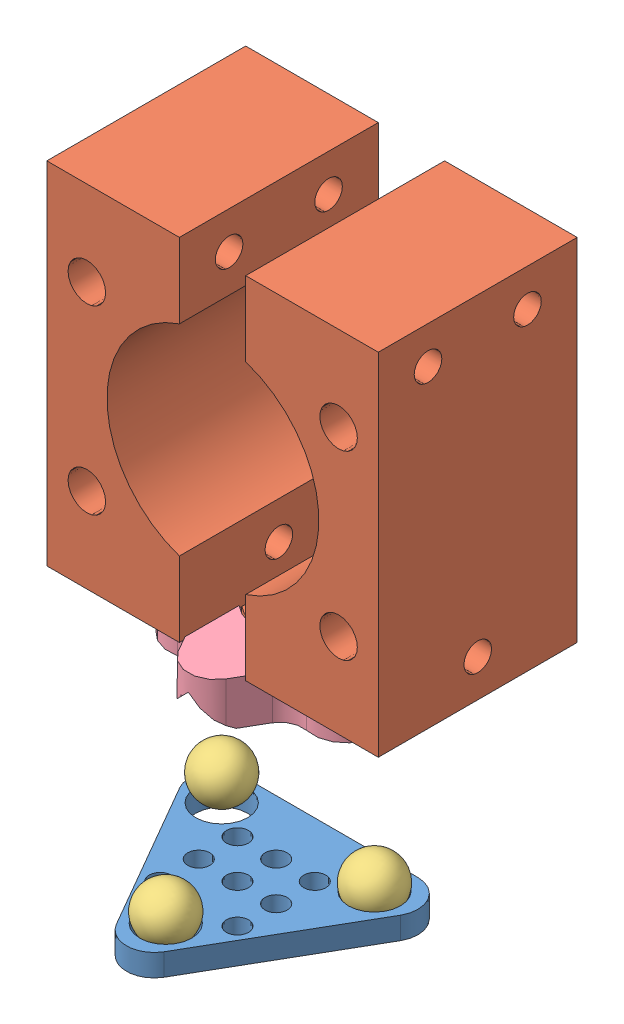
SolidWorks assembly Assembly Ball ground hat magnet, configuration Default. Lengths in mm.
Overall size (30.8 48.2 32.89).
6 component instances, 4 part files, 6 mates.
Components (placement in the parent):
- TricornerHat-1: TricornerHat [Default] at (-0.5926 3.547 -2.2094) size (20.65 2 18.55)
- MagnetHolderC-1: MagnetHolderC [Default] at (-1.0519 14.1713 -13.117) size (30 36.25 18)
- 316Ball-1: 316Ball [Default] at (3.9876 6.2803 6.464) x (0.954549 -0.169167 0.245394) z (-0.280426 -0.230796 0.931716) size (4.76 4.76 4.76)
- 316Ball-2: 316Ball [Default] at (-2.8009 8.6807 -6.0167) x (0.992315 0.113857 0.048462) z (-0.123111 0.947884 0.293871) size (4.76 4.76 4.76)
- 316Ball-3: 316Ball [Default] at (11.2197 5.9138 -5.5133) x (0.650046 0.734726 0.193955) z (0.120986 -0.352051 0.928128) size (4.76 4.76 4.76)
- TricornerGroundE-1: TricornerGroundE [Default] at (-7.151 14.869 -13.2378) size (24.31 4 24.54)
Mates (geometry in assembly coordinates):
- Concentric2: concentric aligned: cylinder of MagnetHolderC-1; cylinder of TricornerGroundE-1
- Concentric4: concentric: cylinder of TricornerHat-1; sphere of 316Ball-3
- Concentric5: concentric: cylinder of TricornerHat-1; sphere of 316Ball-1
- Concentric6: concentric: cylinder of TricornerHat-1; sphere of 316Ball-2
- Tangent5: tangent: plane of TricornerHat-1 through (-3.6136 5.547 -6.7756) normal (0 1 0); sphere of 316Ball-2
- Tangent9: tangent: sphere of 316Ball-2; plane of TricornerHat-1 through (-3.6136 3.547 -6.7756) normal (0 -1 0)
